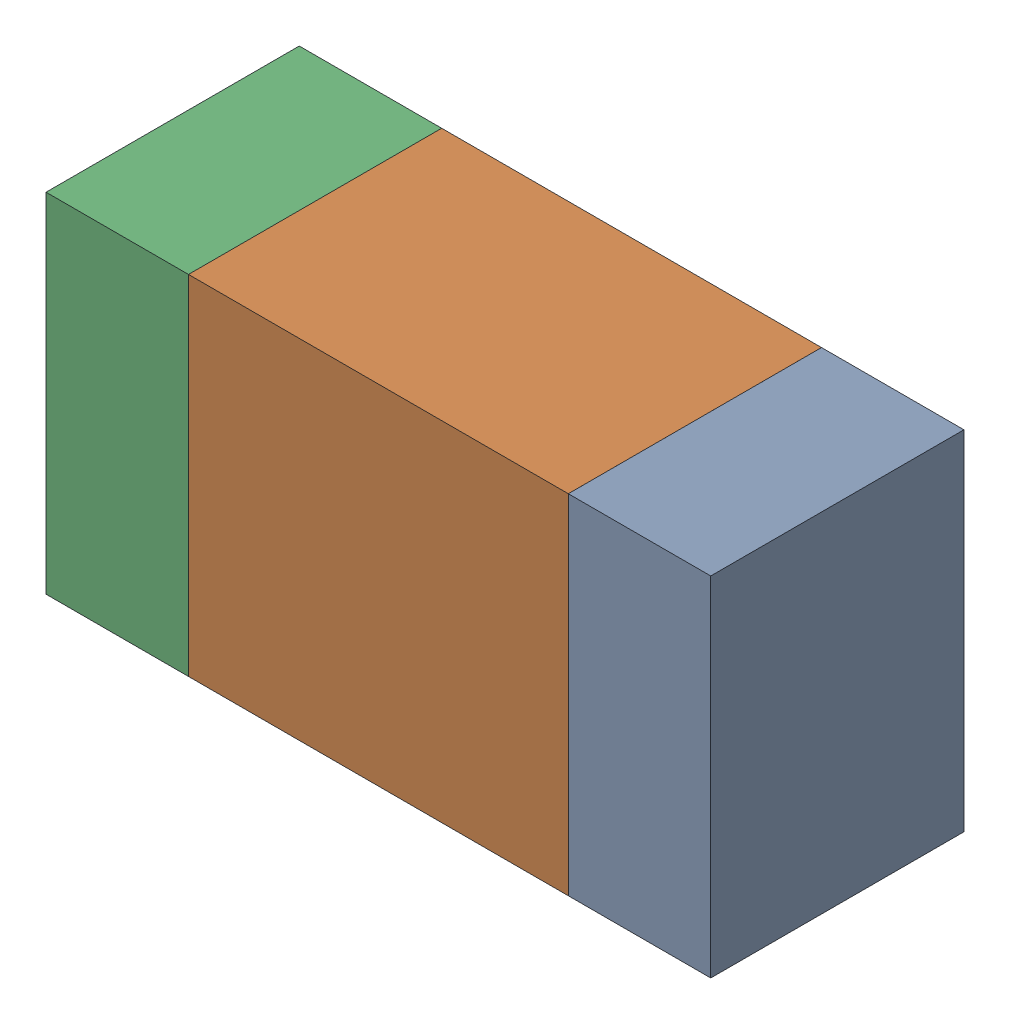
SolidWorks assembly R322_2PCB, configuration Default. Lengths in mm.
Overall size (1.05 0.55 0.4).
6 component instances, 2 part files, 0 mates.
Components (placement in the parent):
- 854785432-1: 854785432 [Default] at (139.6124 87.7001 -2.0638) size (0.22 0.55 0.4)
  - Extruded-1: Extruded [Default] at origin size (0.22 0.55 0.4)
- 854785568-1: 854785568 [Default] at (139.1999 87.7001 -2.0638) size (0.6 0.55 0.4)
  - Extruded_2-1: Extruded_2 [Default] at origin size (0.6 0.55 0.4)
- 854785432-2: 854785432 [Default] at (138.7874 87.7001 -2.0638) size (0.22 0.55 0.4)
  - Extruded-1: Extruded [Default] at origin size (0.22 0.55 0.4)
